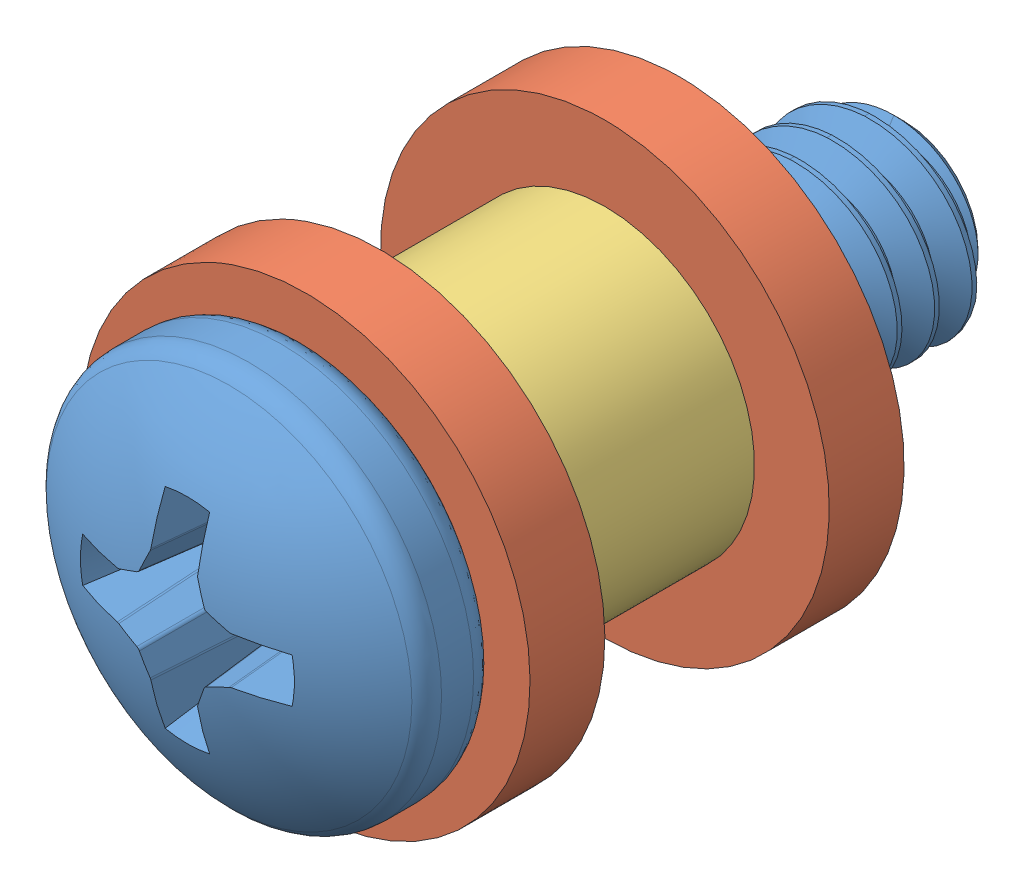
SolidWorks assembly railbutton, configuration Default. Lengths in mm.
Overall size (12.45 12.45 15.68).
4 component instances, 3 part files, 7 mates.
Components (placement in the parent):
- railbutton_screw-1: railbutton_screw [91772A194] at origin size (8.18 8.18 15.68)
- railbutton_washer-1: railbutton_washer [Default] at (0 0 11.1125) x (-0.923728 -0.383049 0) z (-0.383049 0.923728 0) size (9.53 1.59 9.53)
- railbutton_spacer-1: railbutton_spacer [Default] at (0 0 11.1125) x (1 0 0) z (0 1 0) size (6.35 4.76 6.35)
- railbutton_washer-2: railbutton_washer [Default] at (0 0 6.35) x (1 0 0) z (0 1 0) size (9.53 1.59 9.53)
Mates (geometry in assembly coordinates):
- Coincident1: coordinate: point of Screw-1
- Coincident2: coincident aligned: circle of Screw-1; plane of washer-1 through (0 0 12.7) normal (0 0 1)
- Concentric1: concentric aligned: circle of Screw-1; circle of washer-1
- Coincident3: coincident anti-aligned: plane of washer-1 through (0 0 11.1125) normal (0 0 -1); plane of spacer-1 through (0 0 11.1125) normal (0 0 1)
- Concentric2: concentric anti-aligned: circle of washer-1; circle of spacer-1
- Coincident5: coincident anti-aligned: plane of spacer-1 through (0 0 6.35) normal (0 0 -1); plane of washer-2 through (0 0 6.35) normal (0 0 1)
- Concentric3: concentric aligned: circle of spacer-1; circle of washer-2
